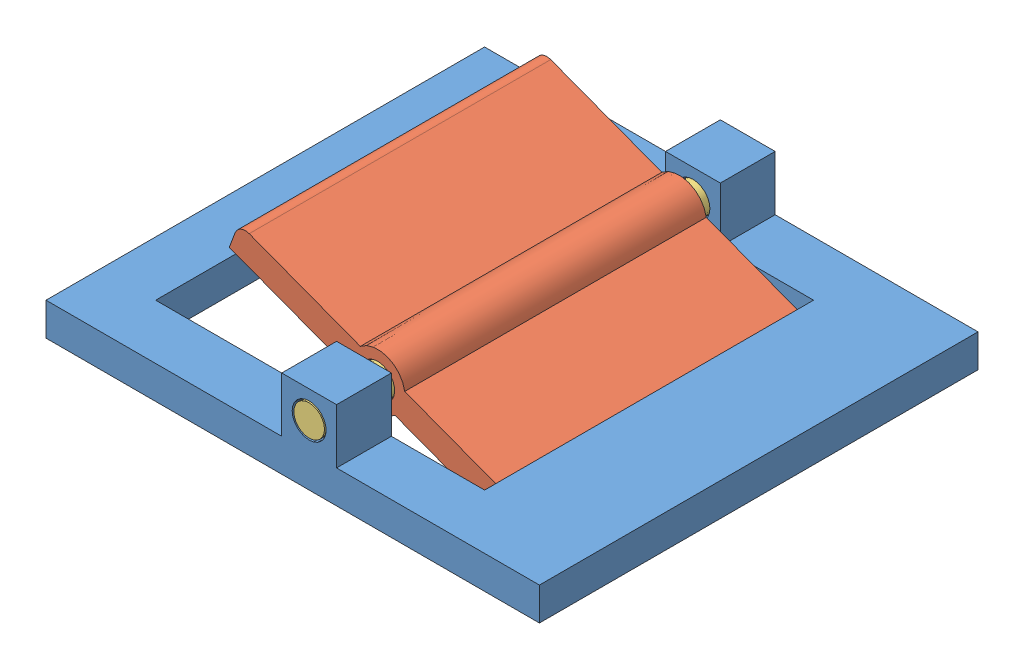
SolidWorks assembly 增高-装配, configuration 默认. Lengths in mm.
Overall size (45 14.59 40).
3 component instances, 3 part files, 4 mates.
Components (placement in the parent):
- 增高件1-1: 增高件1 [默认] at origin size (45 8 40)
- 增高件2-1: 增高件2 [默认] at (1.5 5.5 -13.75) x (0.93528 -0.35391 0) z (0 0 1) size (28 5 27.5)
- 增高件3-1: 增高件3 [默认] at (1.5 5.5 -20) x (0.711496 -0.70269 0) z (0 0 1) size (2.8 2.8 40)
Mates (geometry in assembly coordinates):
- 同心2: concentric aligned: circle of 增高件1-1; circle of 增高件2-1
- 距离3: distance = 13.75 mm anti-aligned: plane of 增高件2-1 through (1.5 5.5 13.75) normal (0 0 1); plane of 增高件1-1 through (0 0 0) normal (0 0 -1)
- 同心3: concentric aligned: circle of 增高件1-1; circle of 增高件3-1
- 重合8: coincident aligned: plane of 增高件1-1 through (-22.5 3 20) normal (0 0 1); plane of 增高件3-1 through (1.5 5.5 20) normal (0 0 1)
